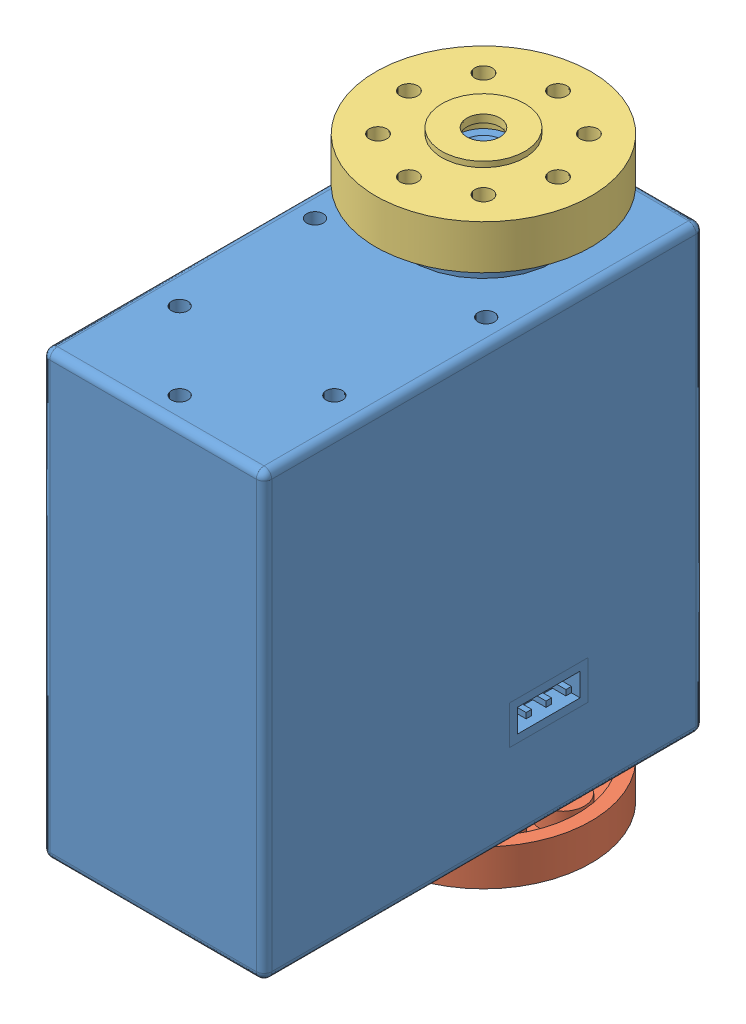
SolidWorks assembly lx224_assem, configuration Default. Lengths in mm.
Overall size (26.99 52.95 43.41).
3 component instances, 3 part files, 4 mates.
Components (placement in the parent):
- LX-224 Servo-1: LX-224 Servo [Predeterminado] at origin size (20.09 51.1 39.82)
- BackHub-1: BackHub [Predeterminado] at (0 -43.9 0) x (-0.837169 0 -0.546944) z (-0.546944 0 0.837169) size (19.5 3.6 19.5)
- FrontHub-1: FrontHub [Predeterminado] at (0 4.75 0) size (19.5 5 19.5)
Mates (geometry in assembly coordinates):
- Distance1: distance = 0.75 mm anti-aligned: plane of FrontHub-1 through (0 2.25 0) normal (0 -1 0); plane of LX-224 Servo-1 through (0 1.5 0) normal (0 1 0)
- Concentric1: concentric: cylinder of LX-224 Servo-1 through (0 1.4 0) axis (0 1 0) radius 1.25; cylinder of FrontHub-1 through (0 6.8 0) axis (0 -1 0) radius 2.5
- Concentric2: concentric aligned: cylinder of LX-224 Servo-1 through (0 -45.7 0) axis (0 1 0) radius 3; cylinder of BackHub-1 through (0 -45.85 0) axis (0 -1 0) radius 3
- Coincident2: coincident aligned: plane of LX-224 Servo-1 through (0 -45.7 0) normal (0 -1 0); plane of BackHub-1 through (0 -45.7 0) normal (0 -1 0)
